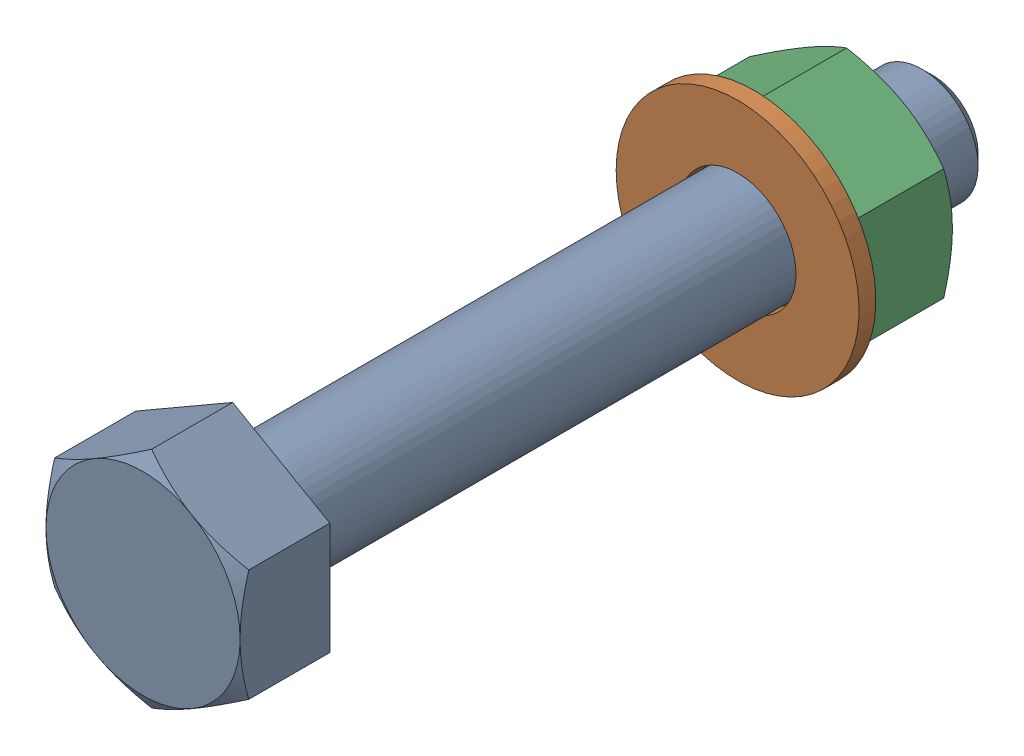
SolidWorks assembly screw_nut_washer_assem, configuration Default. Lengths in mm.
Overall size (52 52 169.2).
3 component instances, 3 part files, 4 mates.
Components (placement in the parent):
- Screw-1: Screw [Default] at (-77.7359 26.257 82.8976) x (0 0 1) z (-1 0 0) size (169.2 48 41.57)
- washer-1: washer [Default] at (-77.7359 26.257 -25.2063) x (0 0 -1) z (1 0 0) size (3.6 52 52)
- nut-2: nut [Default] at (-77.7359 26.257 -50.4063) x (0 0 -1) z (1 0 0) size (21.6 48 41.57)
Mates (geometry in assembly coordinates):
- Concentric2: concentric aligned: cylinder of Screw-1 through (-77.7359 26.257 -67.1024) axis (0 0 1) radius 12; cylinder of washer-1 through (-77.7359 26.257 -28.8063) axis (0 0 1) radius 12.5
- Concentric3: concentric anti-aligned: cylinder of Screw-1 through (-77.7359 26.257 -67.1024) axis (0 0 1) radius 12; cylinder of nut-2 through (-77.7359 26.257 -28.8053) axis (0 0 -1) radius 12
- Coincident2: coincident anti-aligned: plane of washer-1 through (-77.7359 26.257 -28.8063) normal (0 0 -1); plane of nut-2 through (-77.7359 26.257 -28.8063) normal (0 0 1)
- Parallel1: parallel aligned: plane of Screw-1 through (-56.9513 38.257 102.0976) normal (0.5 0.866025 0); plane of nut-2 through (-77.7359 50.257 -28.8063) normal (0.5 0.866025 0)
